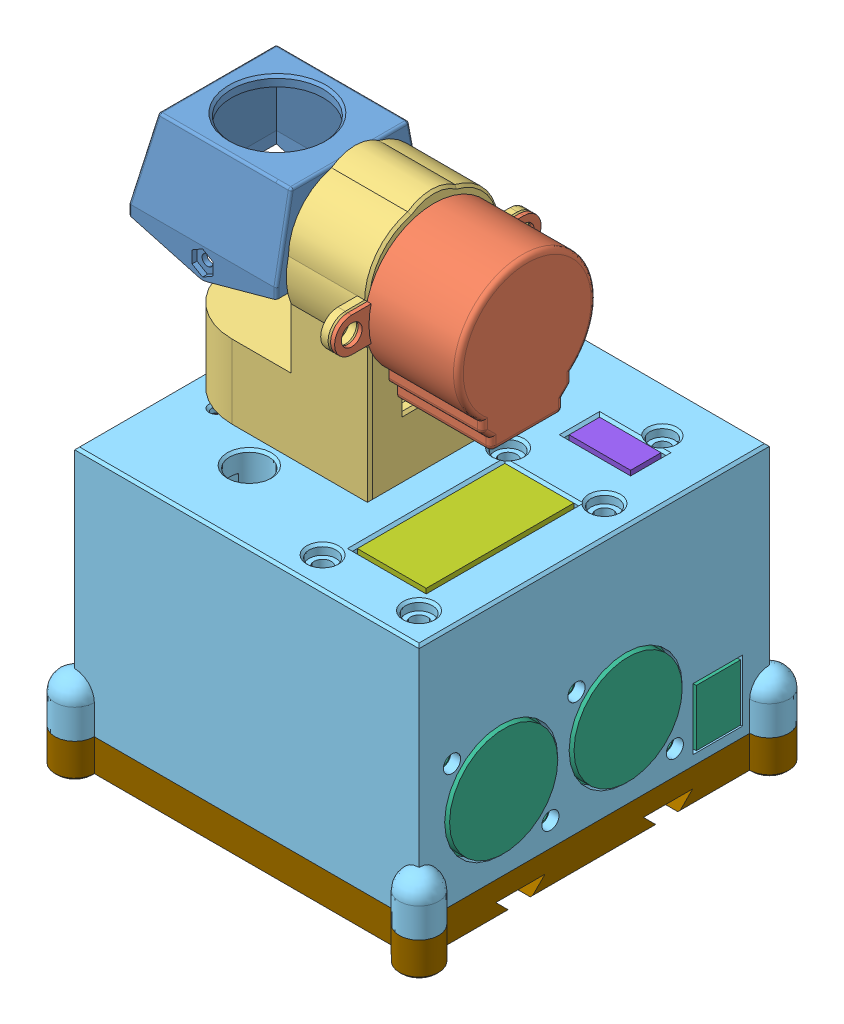
SolidWorks assembly Assem3, configuration Default. Lengths in mm.
Overall size (80 105.61 79.2).
11 component instances, 9 part files, 22 mates.
Components (placement in the parent):
- Head2-1: Head2 [Default] at (-11.812 33.26 36.4007) size (44.5 22 30)
- Step Motor 28BYJ-48-1: Step Motor 28BYJ-48 [Default] at (32.188 27.26 24.4007) x (0 0 1) z (0 -1 0) size (42 29 30.89)
- Yoke3-1: Yoke3 [Default] at origin size (41 61.14 42)
- sensor-2: sensor [Default] at (24.388 14.8919 20.1007) x (0 0 1) z (-1 0 0) size (12.8 7.1 5.8)
- Step Motor 28BYJ-48-2: Step Motor 28BYJ-48 [Default] at (4.188 -29.6316 24.4007) x (0 0 -1) z (1 0 0) size (42 29 30.89)
- Mainbody-1: Mainbody [Default] at origin size (78 49.33 79.2)
- sensor-3: sensor [Default] at (8.488 -21.9316 36.7972) x (-1 0 0) z (0 -1 0) size (12.8 7.1 5.8)
- pcb-1: pcb [Default] at (57.338 -62.2316 53.4007) x (0 0 -1) z (1 0 0) size (65.2 26.6 65.95)
- display-1: display [Default] at (57.188 -22.5816 52.4007) x (0 0 -1) z (0 1 0) size (42.1 24 8.45)
- buttons-1: buttons [Default] at (53.888 -19.7316 8.2007) x (0 0 -1) z (0 1 0) size (19 15.3 5.6)
- Cover-1: Cover [Default] at origin size (78 7 79.2)
Mates (geometry in assembly coordinates):
- Coincident1: coincident anti-aligned: plane of Head2-1 through (28.188 27.26 24.4007) normal (1 0 0); plane of Step Motor 28BYJ-48-1 through (28.188 27.26 24.4007) normal (-1 0 0)
- Concentric5: concentric aligned: cylinder of Head2-1 through (-500011.812 27.26 24.4007) axis (1 0 0) radius 4.7181; cylinder of Step Motor 28BYJ-48-1 through (28.188 27.26 24.4007) axis (1 0 0) radius 2.5
- Parallel5: parallel aligned: plane of Head2-1 through (-14.812 15.26 39.4007) normal (0 0 1); plane of Step Motor 28BYJ-48-1 through (22.188 29.26 25.9007) normal (0 0 1)
- Parallel7: parallel aligned: plane of Head2-1 through (-11.812 33.26 36.4007) normal (0 1 0); plane of sensor-2 through (24.388 21.4919 20.1007) normal (0 1 0)
- Distance2: distance = 1.05 mm anti-aligned: plane of sensor-2 through (24.388 21.4919 20.1007) normal (0 1 0); cylinder of Head2-1 through (-500011.812 27.26 24.4007) axis (1 0 0) radius 4.7181
- Distance3: distance = 6.5 mm aligned: plane of Head2-1 through (-14.812 15.26 39.4007) normal (0 0 1); plane of sensor-2 through (24.388 21.4919 32.9007) normal (0 0 1)
- Coincident2: coincident anti-aligned: plane of Yoke3-1 through (30.188 19.26 24.4007) normal (-1 0 0); plane of sensor-2 through (30.188 21.4919 20.1007) normal (1 0 0)
- Concentric6: concentric anti-aligned: cylinder of Yoke3-1 through (4.188 -25.6316 24.4007) axis (0 1 0) radius 4.7465; cylinder of Step Motor 28BYJ-48-2 through (4.188 -25.6316 24.4007) axis (0 -1 0) radius 2.5
- Parallel8: parallel anti-aligned: plane of Yoke3-1 through (1.938 -25.6316 22.8257) normal (0 0 1); plane of Step Motor 28BYJ-48-2 through (2.188 -19.6316 22.9007) normal (0 0 -1)
- Coincident5: coincident anti-aligned: plane of Yoke3-1 through (4.188 -25.6316 24.4007) normal (0 -1 0); plane of Step Motor 28BYJ-48-2 through (4.188 -25.6316 24.4007) normal (0 1 0)
- Coincident15: coincident anti-aligned: plane of Mainbody-1 through (0 -16.1316 0) normal (0 -1 0); plane of sensor-3 through (8.488 -16.1316 30.1972) normal (0 1 0)
- Distance10: distance = 4.5 mm aligned: plane of sensor-3 through (-4.312 -21.9316 30.1972) normal (-1 0 0); plane of Mainbody-1 through (-8.812 -16.1316 56.4007) normal (-1 0 0)
- Distance11: distance = 1.05 mm anti-aligned: cylinder of Yoke3-1 through (4.188 -25.6316 24.4007) axis (0 1 0) radius 4.7465; plane of sensor-3 through (8.488 -21.9316 30.1972) normal (0 0 -1)
- Coincident17: coincident anti-aligned: plane of Mainbody-1 through (59.188 -63.1316 -12.7993) normal (-1 0 0); plane of pcb-1 through (59.188 -35.6316 26.8007) normal (1 0 0)
- Distance12: distance = 1 mm anti-aligned: plane of pcb-1 through (57.338 -60.6316 -11.7993) normal (0 0 -1); plane of Mainbody-1 through (59.188 -63.1316 -12.7993) normal (0 0 1)
- Distance13: distance = 2 mm anti-aligned: plane of Step Motor 28BYJ-48-2 through (24.3976 -48.6316 16.2829) normal (0 -1 0); plane of pcb-1 through (57.338 -50.6316 53.4007) normal (0 1 0)
- Coincident20: coincident aligned: plane of Mainbody-1 through (0 -14.1316 0) normal (0 1 0); plane of display-1 through (57.188 -14.1316 52.4007) normal (0 1 0)
- Distance14: distance = 2 mm anti-aligned: plane of display-1 through (57.188 -21.3816 52.4007) normal (1 0 0); plane of Mainbody-1 through (59.188 -63.1316 -12.7993) normal (-1 0 0)
- Distance16: distance = 2 mm anti-aligned: plane of Mainbody-1 through (59.188 -63.1316 54.4007) normal (0 0 -1); plane of display-1 through (57.188 -21.3816 52.4007) normal (0 0 1)
- Coincident22: coincident aligned: plane of Mainbody-1 through (0 -14.1316 0) normal (0 1 0); plane of buttons-1 through (53.888 -14.1316 8.2007) normal (0 1 0)
- Distance17: distance = 2 mm anti-aligned: plane of buttons-1 through (53.888 -18.1316 -10.7993) normal (0 0 -1); plane of Mainbody-1 through (59.188 -63.1316 -12.7993) normal (0 0 1)
- Coincident24: coincident aligned: plane of display-1 through (51.788 -14.1316 45.5507) normal (1 0 0); plane of buttons-1 through (51.788 -14.1316 4.0007) normal (1 0 0)
